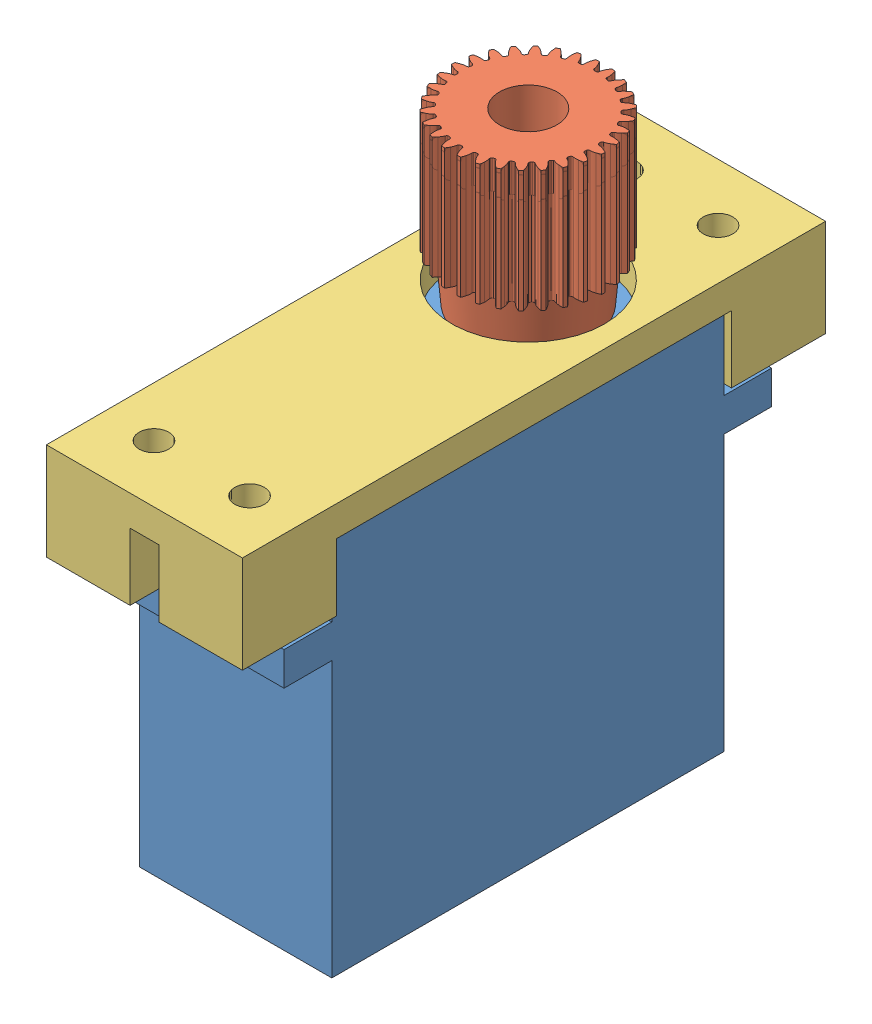
SolidWorks assembly Assem1, configuration Default. Lengths in mm.
Overall size (22.53 58.51 61).
3 component instances, 3 part files, 5 mates.
Components (placement in the parent):
- servoOutline-1: servoOutline [Default] at (-21.3115 -11.3734 11.6313) size (20.1 45.75 51)
- pinion_201007-1: pinion_201007 [Default] at (-11.2615 25.7016 1.5313) x (0 -1 0) z (0.601262 0 -0.799052) size (17.71 16.11 16.06)
- preference_doorServoMountSpacer-1: preference_doorServoMountSpacer [Default] at (-11.2615 8.5016 11.1813) x (0 0 1) z (-1 0 0) size (61 10.18 20.5)
Mates (geometry in assembly coordinates):
- Concentric1: concentric aligned: cylinder of servoOutline-1 through (-11.2615 26.1052 1.5313) axis (0 -1 0) radius 2.9; cylinder of preference_doorServoMountSpacer-1 through (-11.2615 11.6766 1.5313) axis (0 -1 0) radius 8
- Coincident1: coincident anti-aligned: plane of servoOutline-1 through (-1.2115 8.5016 11.6313) normal (0 1 0); plane of preference_doorServoMountSpacer-1 through (-11.2615 8.5016 11.1813) normal (0 -1 0)
- Parallel1: parallel aligned: plane of servoOutline-1 through (-21.3115 -11.3734 11.6313) normal (-1 0 0); plane of preference_doorServoMountSpacer-1 through (-21.5115 11.6766 11.1813) normal (-1 0 0)
- Concentric3: concentric: cylinder of servoOutline-1 through (-11.2615 26.1052 1.5313) axis (0 -1 0) radius 2.9; cylinder of pinion_201007-1 through (-11.2615 62.5538 1.5313) axis (0 1 0) radius 3
- Coincident4: coincident anti-aligned: plane of servoOutline-1 through (-1.2115 14.5016 11.6313) normal (0 1 0); plane of pinion_201007-1 through (-18.31 14.5016 2.3505) normal (0 -1 0)
